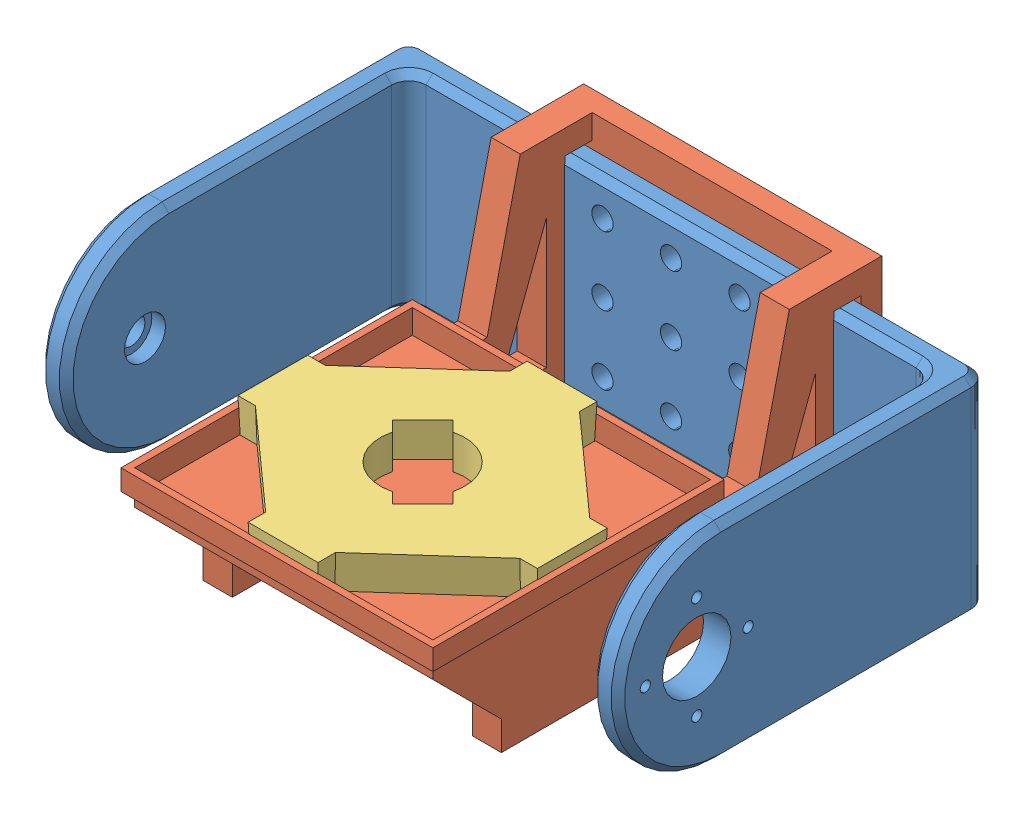
SolidWorks assembly LTE_TAG_Holder, configuration Default. Lengths in mm.
Overall size (170.5 70 133).
3 component instances, 3 part files, 0 mates.
Components (placement in the parent):
- DUT_Bridge-1: DUT_Bridge [Default] at (0 0 -85) x (1 0 0) z (0 -1 0) size (170.5 108 60)
- LTE_TAG_holder-1: LTE_TAG_holder [Default] at (3.85 -162.8742 -55.1496) x (0 0 -1) z (1 0 0) size (133 70 91)
- Part2^LTE_TAG_Holder-1: Part2^LTE_TAG_Holder [Default] at origin size (87.4 10 81.4) (virtual)
